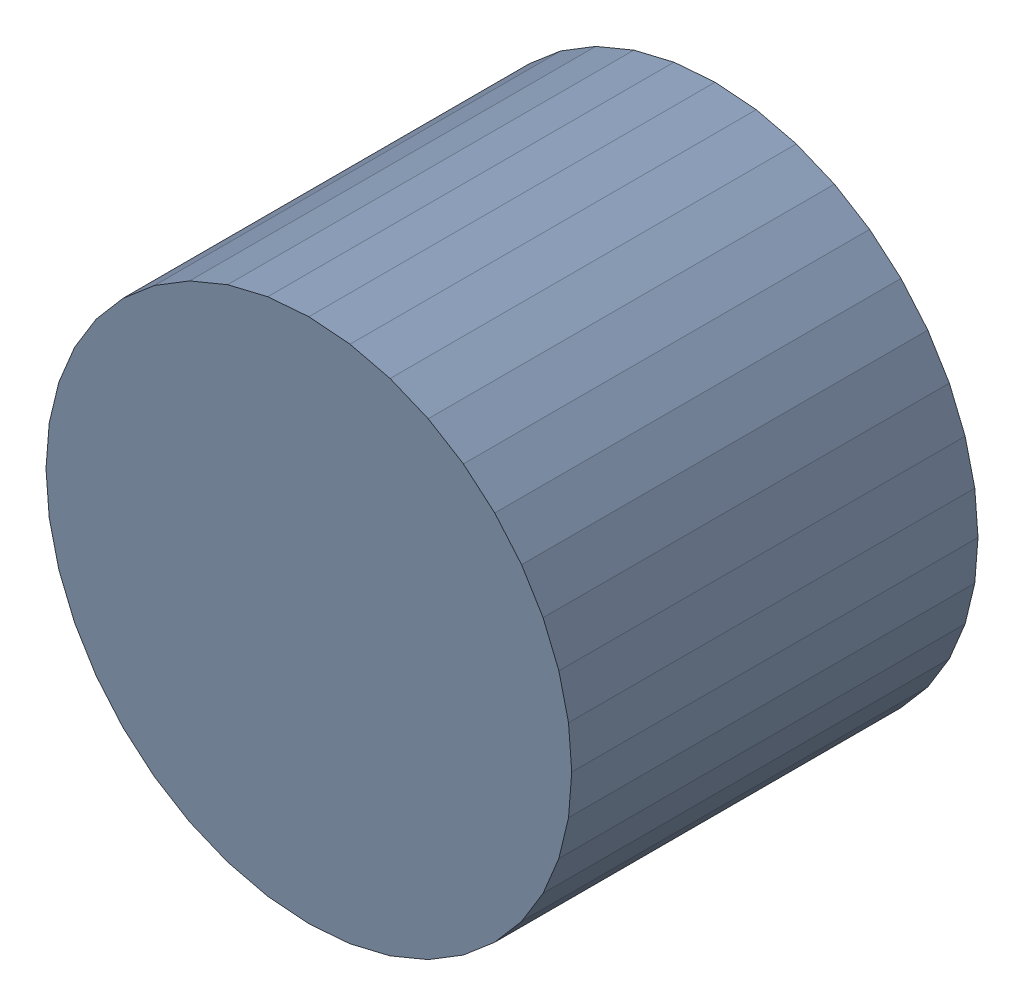
SolidWorks assembly C19Kanaloa_v2.0.0_Power, configuration Default. Lengths in mm.
Overall size (8.02 8.02 6.2).
2 component instances, 1 part files, 0 mates.
Components (placement in the parent):
- 425994496-1: 425994496 [Default] at (91.415 160.68 0) size (8.02 8.02 6.2)
  - Extruded_22-1: Extruded_22 [Default] at origin size (8.02 8.02 6.2)
